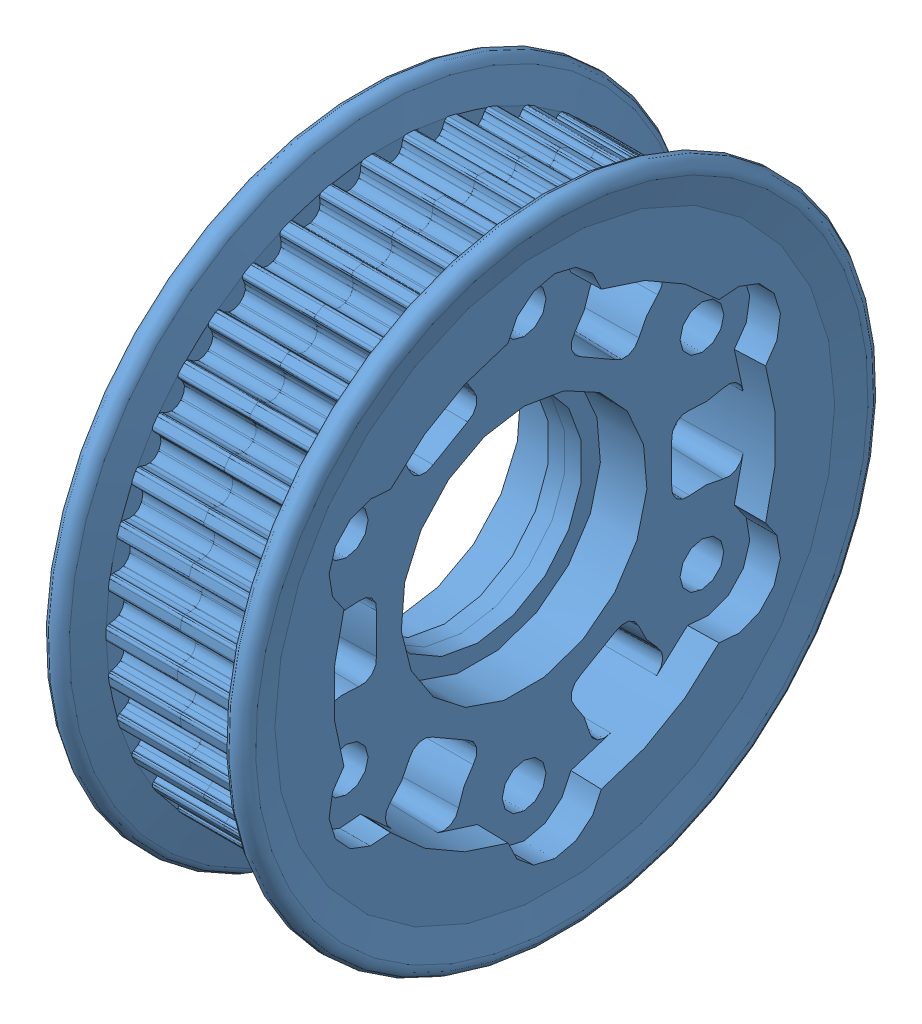
SolidWorks assembly Assem11, configuration Default. Lengths in mm.
Overall size (23.46 74.23 74.23).
2 component instances, 1 part files, 3 mates.
Components (placement in the parent):
- am-2234_42t_trimmed-1: am-2234_42t_trimmed [Default] at origin size (13 74.23 74.23)
- am-2234_42t_trimmed-2: am-2234_42t_trimmed [Default] at (16.6624 0 0) x (-1 0 0) z (0 0.000084 1) size (13 74.23 74.23)
Mates (geometry in assembly coordinates):
- Concentric1: concentric: circle of am-2234_42t_trimmed-1; circle of am-2234_42t_trimmed-2
- Concentric2: concentric: circle of am-2234_42t_trimmed-1; circle of am-2234_42t_trimmed-2
- Coincident1: coincident anti-aligned: plane of am-2234_42t_trimmed-1 through (8.3312 32.198 0.1238) normal (1 0 0); plane of am-2234_42t_trimmed-2 through (8.3312 -32.198 0.1265) normal (-1 0 0)
